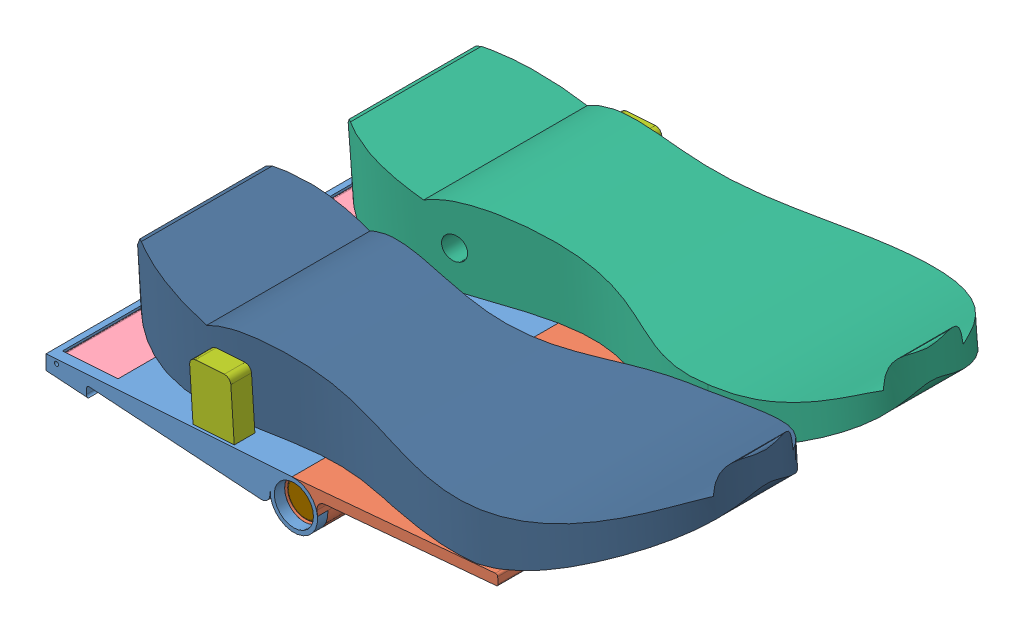
SolidWorks assembly 装配体2, configuration Default. Lengths in mm.
Overall size (292.64 89.46 229.29).
13 component instances, 10 part files, 15 mates.
Components (placement in the parent):
- 充电座_勾子2-1: 充电座_勾子2 [Default] at (152.8847 119.4303 38.823) size (131.5 23 210)
- 充电座_勾子2_背板-1: 充电座_勾子2_背板 [Default] at (152.8847 119.4303 43.823) x (-0.996015 -0.089186 0) z (0 0 1) size (111.5 23 210)
- 充电座_勾子2_支撑板-1: 充电座_勾子2_支撑板 [Default] at (219.8556 133.9611 103.823) x (0.066705 -0.997773 0) z (0 0 1) size (27 4 80)
- 充电座_勾子2_挡板-1: 充电座_勾子2_挡板 [Default] at (38.007 121.2684 43.823) x (0.999026 0.044132 0) z (0 0 1) size (29 4 200)
- 充电座-磁吸头-1: 充电座-磁吸头 [Default] at (111.5385 145.7298 48.823) x (0.999194 0.040143 0) z (0 0 1) size (9.8 9.8 5.2)
- 鞋子类_鞋底38-1: 鞋子类_鞋底38 [Default] at (24.3196 121.5425 152.0399) x (0 0 -1) z (0.081664 -0.99666 0) size (126.78 283.54 56.03)
- 充电座_勾子2_耳朵-1: 充电座_勾子2_耳朵 [Default] at (111.5385 145.7298 48.823) x (-0.997771 -0.066732 0) z (0 0 -1) size (20 32.5 10)
- 充电座_勾子2_耳朵-2: 充电座_勾子2_耳朵 [Default] at (111.5385 145.7298 237.4942) x (0.997771 0.066732 0) z (0 0 1) size (20 32.5 10)
- 充电座-磁吸头-3: 充电座-磁吸头 [Default] at (111.5385 145.7298 237.4942) x (-0.996551 -0.082982 0) z (0 0 -1) size (9.8 9.8 5.2)
- 锂电池6000mah_3962134-1: 锂电池6000mah_3962134 [Default] at (128.0023 115.406 107.4872) x (0 0 1) z (-0.997771 0.066732 0) size (134 3.9 62)
- 锂电池_18650_平头-1: 锂电池_18650_平头 [Default] at (152.8847 119.4303 178.4237) x (-0.988639 -0.150308 0) z (0 0 1) size (18 18 65.2)
- 锂电池_18650_平头-2: 锂电池_18650_平头 [Default] at (152.8847 119.4303 53.9863) x (0.655135 0.755511 0) z (0 0 1) size (18 18 65.2)
- 鞋子类_鞋底38右-1: 鞋子类_鞋底38右 [Default] at (23.7767 122.5736 254.5481) x (0 0 -1) z (0.067719 -0.997704 0) size (120.62 283.54 56.03)
Mates (geometry in assembly coordinates):
- 重合3: coincident anti-aligned: circle of 充电座_勾子2-1; circle of 充电座_勾子2_背板-1
- 重合4: coincident anti-aligned: circle of 充电座_勾子2_背板-1; circle of 充电座_勾子2_支撑板-1
- 重合5: coincident anti-aligned: circle of 充电座_勾子2-1; circle of 充电座_勾子2_挡板-1
- 同心1: concentric anti-aligned: circle of 充电座-磁吸头-1; circle of 充电座_勾子2_耳朵-1
- 重合10: coincident anti-aligned: plane of 充电座-磁吸头-1 through (111.5385 145.7298 43.823) normal (0 0 -1); plane of 充电座_勾子2_耳朵-1 through (111.5385 145.7298 43.823) normal (0 0 1)
- 重合13: coincident anti-aligned: line of 充电座_勾子2-1 through (103.0623 122.6127 43.823) axis (-0.066732 0.997771 0); line of 充电座_勾子2_耳朵-1 through (102.7286 127.6015 43.823) axis (0.066732 -0.997771 0)
- 重合14: coincident anti-aligned: plane of 充电座_勾子2_耳朵-2 through (111.5385 145.7298 242.4942) normal (0 0 -1); plane of 充电座-磁吸头-3 through (111.5385 145.7298 242.4942) normal (0 0 1)
- 同心2: concentric aligned: cylinder of 充电座_勾子2_耳朵-2 through (111.5385 145.7298 242.4942) axis (0 0 -1) radius 7.5; cylinder of 充电座-磁吸头-3 through (111.5385 145.7298 242.4942) axis (0 0 -1) radius 4.9
- 重合15: coincident anti-aligned: line of 充电座_勾子2-1 through (123.0177 123.9473 242.4942) axis (-0.066732 0.997771 0); line of 充电座_勾子2_耳朵-2 through (122.6841 128.9361 242.4942) axis (0.066732 -0.997771 0)
- 重合16: coincident anti-aligned: plane of 充电座_勾子2-1 through (152.4509 125.9158 38.823) normal (-0.066732 0.997771 0); plane of 充电座_勾子2_耳朵-2 through (113.04 123.28 242.4942) normal (0.066732 -0.997771 0)
- 平行1: parallel anti-aligned: line of 充电座_勾子2-1 through (32.8847 122.9303 248.823) axis (0 0 -1); line of 鞋子类_鞋底38-1 through (97.7823 160.8833 51.711) axis (0 0 1)
- 平行2: parallel anti-aligned: line of 充电座_勾子2-1 through (53.6716 119.5512 248.823) axis (0 0 -1); line of 锂电池6000mah_3962134-1 through (66.1405 119.5434 107.4872) axis (0 0 1)
- 同心3: concentric aligned: cylinder of 充电座_勾子2_背板-1 through (152.8847 119.4303 243.823) axis (0 0 -1) radius 9.5; cylinder of 锂电池_18650_平头-2 through (152.8847 119.4303 118.9863) axis (0 0 -1) radius 9
- 同心4: concentric aligned: cylinder of 充电座_勾子2_背板-1 through (152.8847 119.4303 243.823) axis (0 0 -1) radius 9.5; cylinder of 锂电池_18650_平头-1 through (152.8847 119.4303 243.4237) axis (0 0 -1) radius 9
- 重合22: coincident aligned: line of 鞋子类_鞋底38-1 through (97.7823 160.8833 51.711) axis (0 0 1); line of 鞋子类_鞋底38右-1 through (97.7823 160.8833 156.874) axis (0 0 1)
